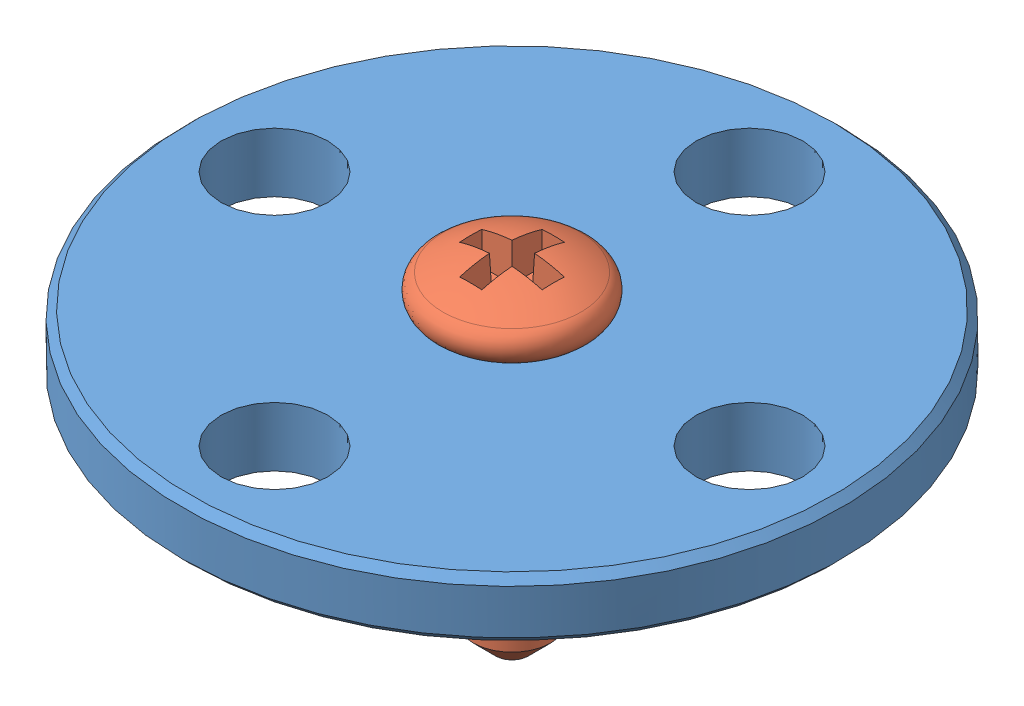
SolidWorks assembly Tetrix Servo Horn (with Screw), configuration Default. Lengths in mm.
Overall size (22.2 11.58 22.2).
2 component instances, 2 part files, 0 mates.
Components (placement in the parent):
- Tetrix Servo Horn-1: Tetrix Servo Horn [Default] at origin size (22.2 6.2 22.2)
- Tetrix Servo Screw-1: Tetrix Servo Screw [Default] at (0 -3.6552 0) size (5.25 11.58 5.25)
